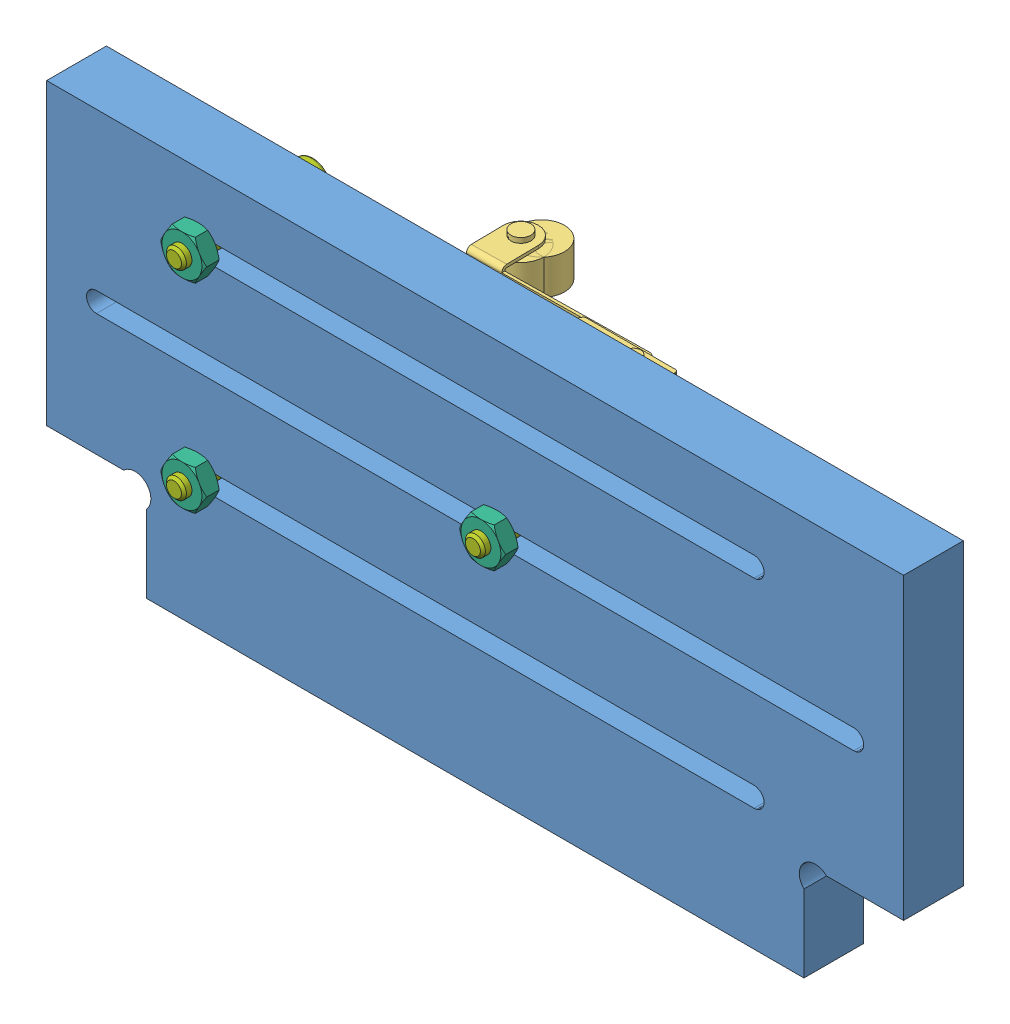
SolidWorks assembly cfc_ferme, configuration Défaut. Lengths in mm.
Overall size (86 40 30.8).
14 component instances, 7 part files, 27 mates.
Components (placement in the parent):
- cfc-platine-1: cfc-platine [Défaut] at (140.8628 -70 0) x (0 0 1) z (0 -1 0) size (6 86 40)
- Grove microswitch v1.0-1: Grove microswitch v1.0 [Défaut] at (-58.8307 23.25 -3.344) x (1 0 0) z (0 1 0) size (41.8 22.4 23.6)
  - PCB grove 20x40-1: PCB grove 20x40 [Défaut] at (-1.988 -1.344 0) size (41.8 1.6 23.6)
  - microswitch 10T85-1: microswitch 10T85 [Défaut] at (9.562 0.256 0) size (22.48 22.4 6.4)
  - Connecteur Grove (coudé CMS)-1: Connecteur Grove (coudé CMS) [Défaut] at (-21.488 0.256 0) x (0 0 -1) z (0 1 0) size (12 10 5)
- entretoise-grove-1: entretoise-grove [Défaut] at (-40.8187 23.25 -2) x (1 0.000242 0) z (0 0 1) size (4 4 2)
- entretoise-grove-2: entretoise-grove [Défaut] at (-70.8187 13.25 -2) size (4 4 2)
- entretoise-grove-3: entretoise-grove [Défaut] at (-70.8187 33.25 -2) size (4 4 2)
- ecrou-h-1: ecrou-h [6007 HU M2] at (-40.8187 23.25 7.6) x (0.866025 -0.5 0) z (-0.5 -0.866025 0) size (4 1.6 4.62)
- ecrou-h-2: ecrou-h [6007 HU M2] at (-70.8187 13.25 7.6) x (0.866025 0.5 0) z (0.5 -0.866025 0) size (4 1.6 4.62)
- ecrou-h-3: ecrou-h [6007 HU M2] at (-70.8187 33.25 7.6) x (-0.866025 0.5 0) z (0.5 0.866025 0) size (4 1.6 4.62)
- vis-chc-1: vis-chc [Vis CHC M2x12] at (-70.8187 13.25 -3.6) x (1 0 0) z (0 1 0) size (3.8 14 3.8)
- vis-chc-2: vis-chc [Vis CHC M2x12] at (-70.8187 33.25 -3.6) x (1 0 0) z (0 1 0) size (3.8 14 3.8)
- vis-chc-3: vis-chc [Vis CHC M2x12] at (-40.8187 23.25 -3.6) x (0.997694 0.067868 0) z (-0.067868 0.997694 0) size (3.8 14 3.8)
Mates (geometry in assembly coordinates):
- Coïncidente1: coincident anti-aligned: plane of cfc-platine-1 through (-8.8686 8.8686 0) normal (0 0 -1)
- Coïncidente2: coincident anti-aligned: plane of cfc-platine-1 through (-10 0 6) normal (0 -1 0)
- Coaxiale1: concentric anti-aligned: cylinder of Grove microswitch v1.0-1/PCB grove 20x40-1 through (-70.8187 33.25 -3.6) axis (0 0 1) radius 1.1; cylinder of entretoise-grove-3 through (-70.8187 33.25 0) axis (0 0 -1) radius 1
- Coïncidente4: coincident anti-aligned: plane of Grove microswitch v1.0-1/PCB grove 20x40-1 through (-60.8187 23.25 -2) normal (0 0 1); plane of entretoise-grove-3 through (-70.8187 33.25 -2) normal (0 0 -1)
- Coaxiale2: concentric anti-aligned: cylinder of Grove microswitch v1.0-1/PCB grove 20x40-1 through (-40.8187 23.25 -3.6) axis (0 0 1) radius 1.1; cylinder of entretoise-grove-1 through (-40.8187 23.25 0) axis (0 0 -1) radius 1
- Coïncidente5: coincident anti-aligned: plane of Grove microswitch v1.0-1/PCB grove 20x40-1 through (-60.8187 23.25 -2) normal (0 0 1); plane of entretoise-grove-1 through (-40.8187 23.25 -2) normal (0 0 -1)
- Coaxiale3: concentric anti-aligned: cylinder of Grove microswitch v1.0-1/PCB grove 20x40-1 through (-70.8187 13.25 -3.6) axis (0 0 1) radius 1.1; cylinder of entretoise-grove-2 through (-70.8187 13.25 0) axis (0 0 -1) radius 1
- Coïncidente6: coincident anti-aligned: plane of Grove microswitch v1.0-1/PCB grove 20x40-1 through (-60.8187 23.25 -2) normal (0 0 1); plane of entretoise-grove-2 through (-70.8187 13.25 -2) normal (0 0 -1)
- Coïncidente7: coincident anti-aligned: plane of cfc-platine-1 through (-8.8686 8.8686 0) normal (0 0 -1); plane of entretoise-grove-1 through (-40.8187 23.25 0) normal (0 0 1)
- Parallèle4: parallel anti-aligned: plane of cfc-platine-1 through (-86 40 6) normal (-1 0 0); plane of Grove microswitch v1.0-1/PCB grove 20x40-1 through (-40.8187 23.25 -3.6) normal (1 0 0)
- Parallèle3: parallel anti-aligned: plane of cfc-platine-1 through (-10 0 6) normal (0 -1 0); plane of Grove microswitch v1.0-1/PCB grove 20x40-1 through (-60.8187 33.25 -3.6) normal (0 1 0)
- Coaxiale4: concentric anti-aligned: cylinder of Grove microswitch v1.0-1/PCB grove 20x40-1 through (-70.8187 13.25 -3.6) axis (0 0 1) radius 1.1; cylinder of vis-chc-1 through (-70.8187 13.25 8.4) axis (0 0 -1) radius 1
- Coaxiale5: concentric anti-aligned: cylinder of Grove microswitch v1.0-1/PCB grove 20x40-1 through (-40.8187 23.25 -3.6) axis (0 0 1) radius 1.1; cylinder of vis-chc-3 through (-40.8187 23.25 8.4) axis (0 0 -1) radius 1
- Coaxiale6: concentric anti-aligned: cylinder of Grove microswitch v1.0-1/PCB grove 20x40-1 through (-70.8187 33.25 -3.6) axis (0 0 1) radius 1.1; cylinder of vis-chc-2 through (-70.8187 33.25 8.4) axis (0 0 -1) radius 1
- Coïncidente11: coincident anti-aligned: plane of Grove microswitch v1.0-1/PCB grove 20x40-1 through (-60.8187 23.25 -3.6) normal (0 0 -1); plane of vis-chc-3 through (-40.8187 23.25 -3.6) normal (0 0 1)
- Coïncidente12: coincident anti-aligned: plane of Grove microswitch v1.0-1/PCB grove 20x40-1 through (-60.8187 23.25 -3.6) normal (0 0 -1); plane of vis-chc-2 through (-70.8187 33.25 -3.6) normal (0 0 1)
- Coïncidente13: coincident anti-aligned: plane of Grove microswitch v1.0-1/PCB grove 20x40-1 through (-60.8187 23.25 -3.6) normal (0 0 -1); plane of vis-chc-1 through (-70.8187 13.25 -3.6) normal (0 0 1)
- Coaxiale7: concentric anti-aligned: cylinder of ecrou-h-2 through (-70.8187 13.25 6) axis (0 0 1) radius 0.7835; cylinder of vis-chc-1 through (-70.8187 13.25 8.4) axis (0 0 -1) radius 1
- Coaxiale8: concentric anti-aligned: cylinder of ecrou-h-3 through (-70.8187 33.25 6) axis (0 0 1) radius 0.7835; cylinder of vis-chc-2 through (-70.8187 33.25 8.4) axis (0 0 -1) radius 1
- Coaxiale9: concentric anti-aligned: cylinder of ecrou-h-1 through (-40.8187 23.25 6) axis (0 0 1) radius 0.7835; cylinder of vis-chc-3 through (-40.8187 23.25 8.4) axis (0 0 -1) radius 1
- Coïncidente14: coincident anti-aligned: plane of cfc-platine-1 through (-8.8686 8.8686 6) normal (0 0 1); plane of ecrou-h-2 through (-69.664 15.25 6) normal (0 0 -1)
- Coïncidente15: coincident anti-aligned: plane of cfc-platine-1 through (-8.8686 8.8686 6) normal (0 0 1); plane of ecrou-h-1 through (-38.5093 23.25 6) normal (0 0 -1)
- Coïncidente16: coincident anti-aligned: plane of cfc-platine-1 through (-8.8686 8.8686 6) normal (0 0 1); plane of ecrou-h-3 through (-73.1281 33.25 6) normal (0 0 -1)
- Parallèle5: parallel aligned: plane of cfc-platine-1 through (0 40 6) normal (0 1 0); plane of ecrou-h-2 through (-69.664 15.25 6) normal (0 1 0)
- Parallèle6: parallel aligned: plane of ecrou-h-1 through (-39.664 25.25 6) normal (0 1 0); plane of ecrou-h-2 through (-69.664 15.25 6) normal (0 1 0)
- Parallèle7: parallel aligned: plane of ecrou-h-2 through (-69.664 15.25 6) normal (0 1 0); plane of ecrou-h-3 through (-69.664 35.25 6) normal (0 1 0)
- Tangent1: tangent anti-aligned: plane of cfc-platine-1 through (-5 22.25 6) normal (0 1 0); cylinder of vis-chc-3 through (-40.8187 23.25 8.4) axis (0 0 -1) radius 1
